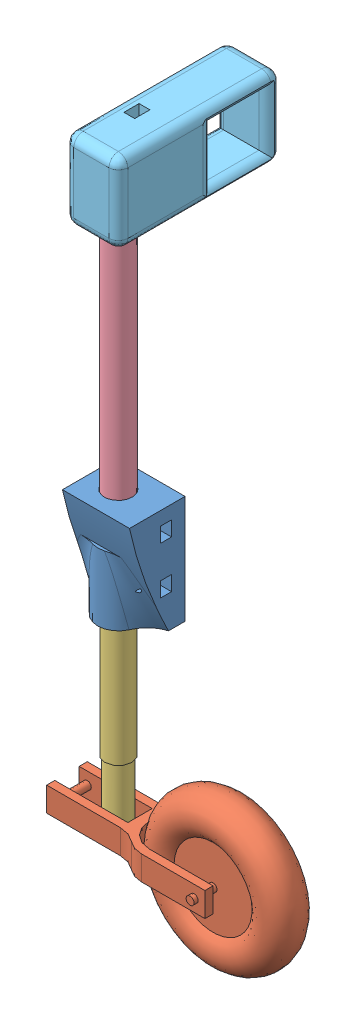
SolidWorks assembly right rear gear, configuration Default. Lengths in mm.
Overall size (86.5 247.1 63.95).
5 component instances, 5 part files, 11 mates.
Components (placement in the parent):
- rear gear part 1-1: rear gear part 1 [Default] at (22.7002 5.5024 14.7192) size (24.8 40 20.53)
- wheel-1: wheel [Default] at (16.0502 -63.9976 24.7192) x (0 0 -1) z (0 1 0) size (27 86.5 55)
- landing gear main rod-1: landing gear main rod [Default] at (8.0502 25.5024 24.7192) x (-1 0 0) z (0 0 1) size (10 90 10)
- carbon fiber support-1: carbon fiber support [Default] at (8.0502 150.5024 24.7192) x (-0.837169 0 -0.546944) z (-0.546944 0 0.837169) size (10 120 10)
- main support of rear gear-1: main support of rear gear [Default] at (18.0502 134.5024 -20.7308) x (0 0 1) z (0 -1 0) size (60.45 20 29.6)
Mates (geometry in assembly coordinates):
- Concentric1: concentric anti-aligned: cylinder of wheel-1 through (8.0502 -59.4976 36.4618) axis (0 0 -1) radius 1.5; cylinder of landing gear main rod-1 through (8.0502 -59.4976 -7.7808) axis (0 0 1) radius 1.5
- Parallel1: parallel anti-aligned: plane of wheel-1 through (16.2721 -54.9976 42.2192) normal (0 1 0); plane of landing gear main rod-1 through (8.0502 -64.4976 24.7192) normal (0 -1 0)
- Width1: width: line of wheel-1; plane of landing gear main rod-1 through (-10.9498 -54.9976 17.2192) normal (0 0 -1); axis of wheel-1 through (8.0502 -64.4976 24.7192) axis (0 1 0)
- Concentric2: concentric anti-aligned: cylinder of rear gear part 1-1 through (8.0502 25.5024 24.7192) axis (0 -1 0) radius 5.15; cylinder of landing gear main rod-1 through (8.0502 -39.4976 24.7192) axis (0 1 0) radius 5
- Perpendicular1: perpendicular: plane of rear gear part 1-1 through (-2.0998 45.5024 14.7192) normal (-1 0 0); plane of wheel-1 through (52.0502 -54.9976 36.7192) normal (0 0 1)
- Coincident3: coincident anti-aligned: plane of rear gear part 1-1 through (8.0502 25.5024 24.7192) normal (0 -1 0); plane of landing gear main rod-1 through (8.0502 25.5024 24.7192) normal (0 1 0)
- Coincident4: coincident anti-aligned: plane of rear gear part 1-1 through (8.0502 30.5024 24.7192) normal (0 1 0); plane of carbon fiber support-1 through (8.0502 30.5024 24.7192) normal (0 -1 0)
- Concentric3: concentric anti-aligned: cylinder of rear gear part 1-1 through (8.0502 50.5024 24.7192) axis (0 -1 0) radius 5.15; cylinder of carbon fiber support-1 through (8.0502 30.5024 24.7192) axis (0 1 0) radius 5
- Coincident5: coincident anti-aligned: plane of carbon fiber support-1 through (8.0502 150.5024 24.7192) normal (0 1 0); plane of main support of rear gear-1 through (18.0502 150.5024 -20.7308) normal (0 -1 0)
- Concentric4: concentric anti-aligned: cylinder of carbon fiber support-1 through (8.0502 30.5024 24.7192) axis (0 1 0) radius 5; cylinder of main support of rear gear-1 through (8.0502 150.5024 24.7192) axis (0 -1 0) radius 5.15
- Parallel3: parallel aligned: plane of rear gear part 1-1 through (22.7002 45.5024 14.7192) normal (0 0 -1); plane of main support of rear gear-1 through (-1.9498 134.5024 -25.7308) normal (0 0 -1)
